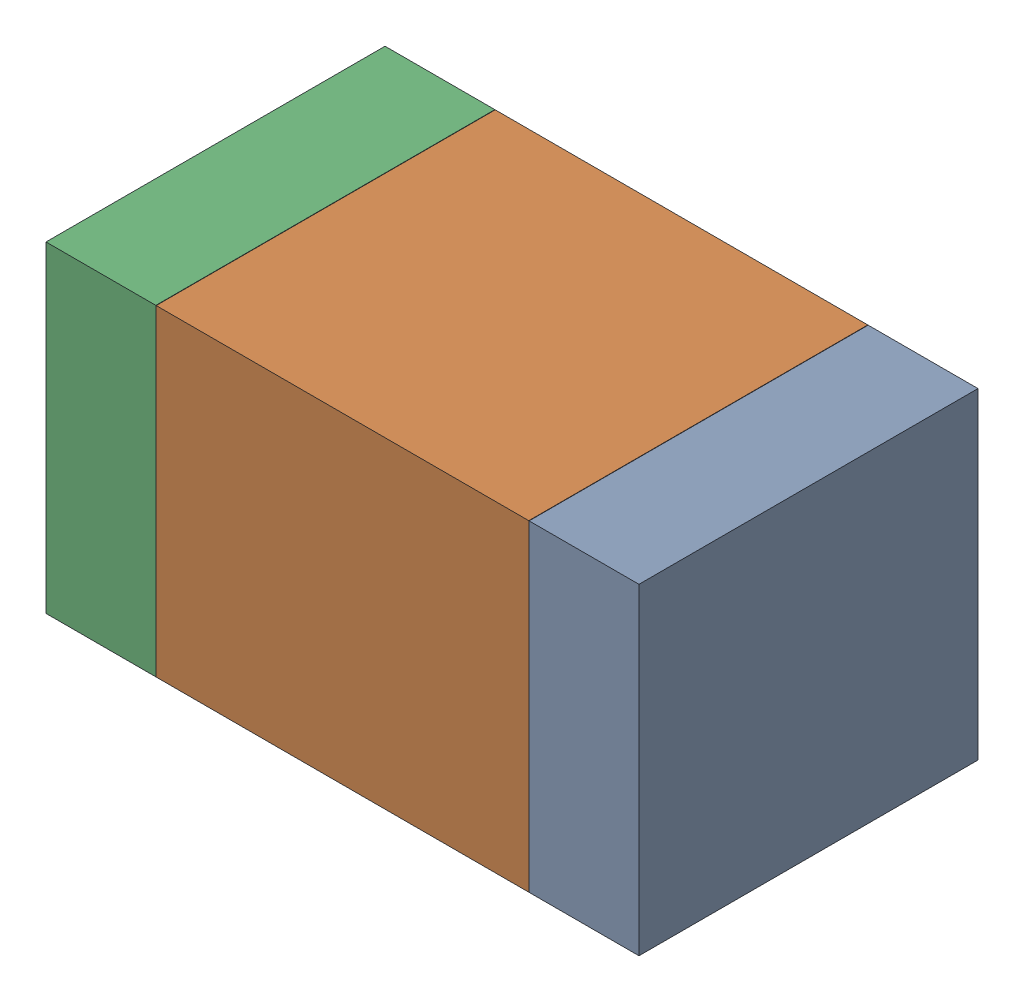
SolidWorks assembly C8, configuration Default. Lengths in mm.
Overall size (1.75 0.95 1).
6 component instances, 2 part files, 0 mates.
Components (placement in the parent):
- 6575498272-1: 6575498272 [Default] at (23.0645 17.272 0) size (0.32 0.95 1)
  - Extruded_8-1: Extruded_8 [Default] at origin size (0.32 0.95 1)
- 6575498112-1: 6575498112 [Default] at (22.352 17.272 0) size (1.1 0.95 1)
  - Extruded_9-1: Extruded_9 [Default] at origin size (1.1 0.95 1)
- 6575498272-2: 6575498272 [Default] at (21.6395 17.272 0) size (0.32 0.95 1)
  - Extruded_8-1: Extruded_8 [Default] at origin size (0.32 0.95 1)
